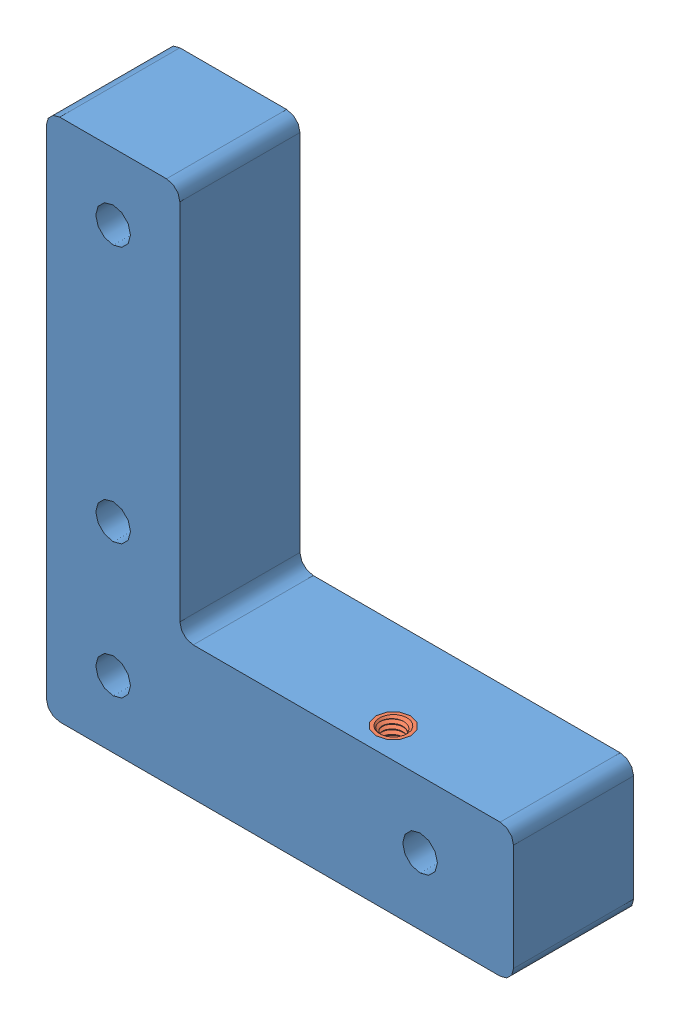
SolidWorks assembly tall_motor_corner_plate_spacer_with_insert, configuration Default. Lengths in mm.
Overall size (85 78.5 23.2).
2 component instances, 2 part files, 4 mates.
Components (placement in the parent):
- motor_corner_bracket_spacer-1: motor_corner_bracket_spacer [Right Motor Corner Bracket Spacer] at (-213.4548 157 -10) x (0 -1 0) z (-1 0 0) size (78.5 23.2 85)
- m4_heat_set_insert_long_94180A353-1: m4_heat_set_insert_long_94180A353 [94180A353] at (-165.9548 20 -4.5) x (0.989318 0 -0.145772) z (0.145772 0 0.989318) size (6.35 8.38 6.35)
Mates (geometry in assembly coordinates):
- Coincident1594070438: coincident aligned: plane of motor_corner_bracket_spacer-1 through (-193.4548 20 0) normal (0 1 0); plane of m4_heat_set_insert_long_94180A353-1 through (-165.9548 20 -4.5) normal (0 1 0)
- Concentric754009881: concentric anti-aligned: cylinder of motor_corner_bracket_spacer-1 through (-165.9548 78.5 -4.5) axis (0 -1 0) radius 2.6; cylinder of m4_heat_set_insert_long_94180A353-1 through (-165.9548 15.6965 -4.5) axis (0 1 0) radius 2.97
- Coincident1594070439: coincident aligned: plane of motor_corner_bracket_spacer-1 through (-213.4548 0 0) normal (0 0 1)
- Coincident1594070441: coincident anti-aligned: plane of motor_corner_bracket_spacer-1 through (-143.4548 0 0) normal (0 -1 0)
